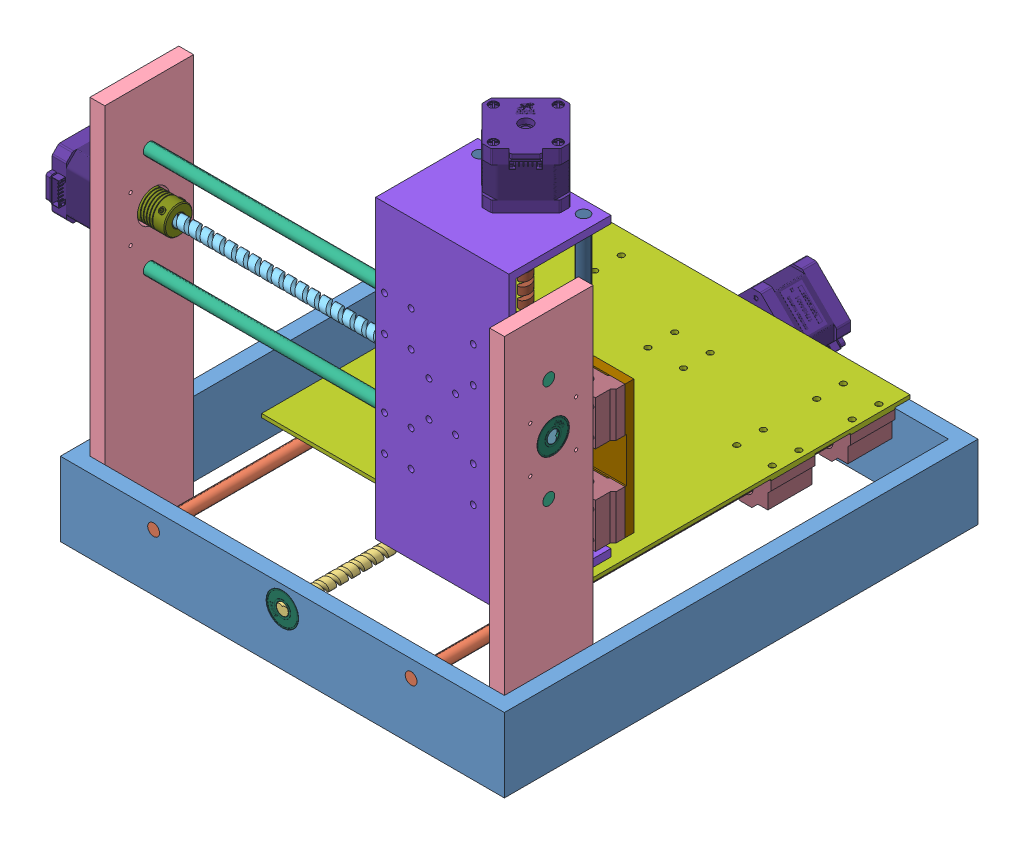
SolidWorks assembly INK Machine 2022, configuration Predeterminado. Lengths in mm.
Overall size (542.6 565 483.23).
40 component instances, 17 part files, 113 mates.
Components (placement in the parent):
- realBASE-1: realBASE [Predeterminado] at (-71.4442 -39.2888 240) size (300 50 320)
- realbarra-1: realbarra [Predeterminado] at (-158.4442 -0.7888 80) x (-0.034704 -0.999398 0) z (0 0 1) size (8 8 320)
- realbarra-2: realbarra [Predeterminado] at (15.5558 -0.7888 80) size (8 8 320)
- realtornillo-1: realtornillo [Predeterminado] at (-71.4442 -3.7888 105) x (-0.003638 0.999993 0) z (0 0 1) size (8.21 8.21 483.23)
- realViga superior-1: realViga superior [Predeterminado] at (68.5558 90.7112 360) x (0 0 1) z (-1 0 0) size (60 260 10)
- realViga superior-2: realViga superior [Predeterminado] at (-201.4442 90.7112 360) x (0 0 1) z (-1 0 0) size (60 260 10)
- realtornillo2-1: realtornillo2 [Predeterminado] at (68.5558 145.7112 357) x (0 0.604417 -0.796668) z (-1 0 0) size (8.21 8.21 482.99)
- realbarra2-1: realbarra2 [Predeterminado] at (68.5558 180.7112 360) x (0 0.764966 -0.644071) z (-1 0 0) size (8 8 280)
- realbarra2-2: realbarra2 [Predeterminado] at (68.5558 110.7112 360) x (0 0.924225 0.381849) z (-1 0 0) size (8 8 280)
- realcama-1: realcama [Predeterminado] at (-71.4442 11.2112 127.5) size (208 3.5 230)
- realCaja superior-5: realCaja superior [Predeterminado] at (13.5558 145.7112 372) x (1 0 0) z (0 0 -1) size (90 200 69)
- realCAMA SUPERIOR-1: realCAMA SUPERIOR [Predeterminado] at (13.5558 104.1528 304.5) x (-1 0 0) z (0 0 -1) size (104 90 6)
- realbarra3-1: realbarra3 [Predeterminado] at (-21.4442 45.7112 316.5) size (8 200 8)
- realbarra3-2: realbarra3 [Predeterminado] at (48.5558 45.7112 316.5) size (8 200 8)
- realtornillo3-1: realtornillo3 [Predeterminado] at (13.5558 222.7112 320.5) x (-0.818193 0 0.574943) z (0 -1 0) size (8.21 8.21 482.52)
- realReklaampastakas 1.step-2: realReklaampastakas 1.step [Predeterminado] at (20.5558 37.5028 293.65) size (20 138.6 10.7)
- realSC8UU.step-1: realSC8UU.step [Predeterminado] at (15.5558 -0.7888 105) size (34 22 30)
- realSC8UU.step-2: realSC8UU.step [Predeterminado] at (-158.4442 -0.7888 105) size (34 22 30)
- realSC8UU.step-3: realSC8UU.step [Predeterminado] at (-158.4442 -0.7888 159) size (34 22 30)
- realSC8UU.step-4: realSC8UU.step [Predeterminado] at (15.5558 -0.7888 159) size (34 22 30)
- realcamisa-1: realcamisa [Predeterminado] at (-71.4442 10.2112 132) x (-1 0 0) z (0 0 1) size (35 28 30)
- realKFL08 - Mancal Flange oval Ø8.stp-1: realKFL08 - Mancal Flange oval Ø8.stp [Predeterminado] at (-71.4442 -3.7888 400.5) x (1 0 0) z (0 1 0) size (22 10.85 22)
- realCHINA_Coupling flexible_D19L25_6,35x8.stp-1: realCHINA_Coupling flexible_D19L25_6,35x8.stp [Predeterminado] at (-71.4442 -3.7888 94.5) x (-0.303541 -0.952818 0) z (-0.952818 0.303541 0) size (19.02 25 19.01)
- realNema 17 Motor a Pasos 17HS4401-1: realNema 17 Motor a Pasos 17HS4401 [Predeterminado] at (-71.4442 -3.7888 42.5) x (0.707107 0.707107 0) z (0 0 1) size (42.2 46.7 62.65)
- realKFL08 - Mancal Flange oval Ø8.stp-2: realKFL08 - Mancal Flange oval Ø8.stp [Predeterminado] at (69.0558 145.7112 357) x (0 -0.381849 0.924225) z (0 -0.924225 -0.381849) size (22 10.85 22)
- realCHINA_Coupling flexible_D19L25_6,35x8.stp-2: realCHINA_Coupling flexible_D19L25_6,35x8.stp [Predeterminado] at (-196.9442 145.7112 357) x (0 -1 0) z (0 0 1) size (19.02 25 19.01)
- realNema 17 Motor a Pasos 17HS4401-2: realNema 17 Motor a Pasos 17HS4401 [Predeterminado] at (-248.9442 145.7112 357) x (0 -1 0) z (1 0 0) size (42.2 46.7 62.65)
- realSC8UU.step-5: realSC8UU.step [Predeterminado] at (-16.4442 110.7112 360) x (0 1 0) z (1 0 0) size (34 22 30)
- realSC8UU.step-6: realSC8UU.step [Predeterminado] at (43.5558 110.7112 360) x (0 1 0) z (1 0 0) size (34 22 30)
- realSC8UU.step-7: realSC8UU.step [Predeterminado] at (43.5558 180.7112 360) x (0 1 0) z (1 0 0) size (34 22 30)
- realSC8UU.step-8: realSC8UU.step [Predeterminado] at (-16.4442 180.7112 360) x (0 1 0) z (1 0 0) size (34 22 30)
- realcamisa-2: realcamisa [Predeterminado] at (13.5558 145.7112 371) x (0 -1 0) z (1 0 0) size (35 28 30)
- realSC8UU.step-9: realSC8UU.step [Predeterminado] at (-21.4442 134.1528 316.5) x (1 0 0) z (0 1 0) size (34 22 30)
- realSC8UU.step-10: realSC8UU.step [Predeterminado] at (-21.4442 74.1528 316.5) x (1 0 0) z (0 1 0) size (34 22 30)
- realSC8UU.step-11: realSC8UU.step [Predeterminado] at (48.5558 134.1528 316.5) x (1 0 0) z (0 1 0) size (34 22 30)
- realSC8UU.step-12: realSC8UU.step [Predeterminado] at (48.5558 74.1528 316.5) x (1 0 0) z (0 1 0) size (34 22 30)
- realKFL08 - Mancal Flange oval Ø8.stp-3: realKFL08 - Mancal Flange oval Ø8.stp [Predeterminado] at (13.5558 45.2112 320.5) size (22 10.85 22)
- realNema 17 Motor a Pasos 17HS4401-3: realNema 17 Motor a Pasos 17HS4401 [Predeterminado] at (13.5558 283.2112 320.5) x (-0.707107 0 0.707107) z (0 -1 0) size (42.2 46.7 62.65)
- realCHINA_Coupling flexible_D19L25_6,35x8.stp-3: realCHINA_Coupling flexible_D19L25_6,35x8.stp [Predeterminado] at (13.5558 231.2112 320.5) x (0.56381 0 0.825904) z (0.825904 0 -0.56381) size (19.02 25 19.01)
- realcamisa-3: realcamisa [Predeterminado] at (13.5558 104.1528 306.5) x (1 0 0) z (0 -1 0) size (35 28 30)
Mates (geometry in assembly coordinates):
- Coincidente1: coincident aligned: plane of BASE-1 through (-221.4442 10.7112 400) normal (0 0 1); plane of tornillo-1 through (-71.4442 -3.7888 400) normal (0 0 1)
- Concéntrica7: concentric aligned: circle of BASE-1; circle of tornillo-1
- Coincidente3: coincident aligned: plane of BASE-1 through (-221.4442 10.7112 400) normal (0 0 1); plane of barra-1 through (-158.4442 -0.7888 400) normal (0 0 1)
- Concéntrica3: concentric aligned: circle of BASE-1; circle of barra-1
- Concéntrica4: concentric aligned: circle of BASE-1; circle of barra-2
- Coincidente6: coincident anti-aligned: plane of BASE-1 through (-211.4442 10.7112 90) normal (1 0 0); plane of Viga superior-2 through (-211.4442 90.7112 360) normal (-1 0 0)
- Coincidente7: coincident anti-aligned: plane of BASE-1 through (-211.4442 10.7112 390) normal (0 0 -1); plane of Viga superior-2 through (-211.4442 220.7112 390) normal (0 0 1)
- Coincidente8: coincident aligned: plane of BASE-1 through (-71.4442 -39.2888 240) normal (0 -1 0); plane of Viga superior-2 through (-211.4442 -39.2888 330) normal (0 -1 0)
- Coincidente9: coincident anti-aligned: plane of BASE-1 through (68.5558 10.7112 90) normal (-1 0 0); plane of Viga superior-1 through (68.5558 90.7112 360) normal (1 0 0)
- Coincidente10: coincident: point of BASE-1; point of Viga superior-1
- Coincidente11: coincident aligned: plane of BASE-1 through (-71.4442 -39.2888 240) normal (0 -1 0); plane of Viga superior-1 through (58.5558 -39.2888 330) normal (0 -1 0)
- Concéntrica11: concentric aligned: circle of Viga superior-1; circle of tornillo2-1
- Concéntrica10: concentric aligned: circle of Viga superior-1; circle of barra2-1
- Concéntrica12: concentric aligned: circle of Viga superior-1; circle of barra2-2
- Paralelo3: parallel anti-aligned: plane of BASE-1 through (-71.4442 -39.2888 240) normal (0 -1 0); plane of cama-1 through (-71.4442 13.7112 127.5) normal (0 1 0)
- Coincidente26: coincident aligned: plane of BASE-1 through (-221.4442 10.7112 400) normal (0 0 1); plane of barra-2 through (15.5558 -0.7888 400) normal (0 0 1)
- Paralelo4: parallel aligned: plane of Viga superior-1 through (68.5558 90.7112 360) normal (1 0 0); plane of barra2-1 through (68.5558 180.7112 360) normal (1 0 0)
- Coincidente29: coincident aligned: plane of Viga superior-1 through (68.5558 90.7112 360) normal (1 0 0); plane of barra2-2 through (68.5558 110.7112 360) normal (1 0 0)
- Coincidente30: coincident aligned: plane of Viga superior-1 through (68.5558 90.7112 360) normal (1 0 0); plane of barra2-1 through (68.5558 180.7112 360) normal (1 0 0)
- Coincidente31: coincident aligned: plane of Viga superior-1 through (68.5558 90.7112 360) normal (1 0 0); plane of tornillo2-1 through (68.5558 145.7112 357) normal (1 0 0)
- Paralelo9: parallel anti-aligned: plane of cama-1 through (-71.4442 13.7112 127.5) normal (0 1 0); plane of Caja superior-5 through (-31.4442 45.7112 377) normal (0 -1 0)
- Concéntrica27: concentric anti-aligned: circle of Caja superior-5; circle of barra3-2
- Coincidente40: coincident aligned: plane of Caja superior-5 through (-31.4442 245.7112 377) normal (0 1 0); plane of barra3-2 through (48.5558 245.7112 316.5) normal (0 1 0)
- Concéntrica28: concentric anti-aligned: circle of Caja superior-5; circle of barra3-1
- Coincidente41: coincident aligned: plane of Caja superior-5 through (-31.4442 245.7112 377) normal (0 1 0); plane of barra3-1 through (-21.4442 245.7112 316.5) normal (0 1 0)
- Coincidente42: coincident aligned: plane of tornillo3-1 through (13.5558 45.7112 320.5) normal (0 -1 0); plane of Caja superior-5 through (-31.4442 45.7112 377) normal (0 -1 0)
- Concéntrica29: concentric aligned: circle of Caja superior-5; circle of tornillo3-1
- Paralelo12: parallel aligned: plane of Viga superior-1 through (68.5558 90.7112 360) normal (1 0 0); plane of CAMA SUPERIOR-1 through (65.5558 59.1528 299.5) normal (1 0 0)
- Coincidente51: coincident anti-aligned: plane of CAMA SUPERIOR-1 through (13.5558 104.1528 299.5) normal (0 0 -1); plane of Reklaampastakas 1.step-2 through (20.5558 37.5028 299.5) normal (0 0 1)
- Coincidente52: coincident aligned: plane of CAMA SUPERIOR-1 through (65.5558 149.1528 299.5) normal (0 1 0); plane of Reklaampastakas 1.step-2 through (30.5558 149.1528 299.5) normal (0 1 0)
- Distancia1: distance = 35 mm aligned: plane of CAMA SUPERIOR-1 through (65.5558 59.1528 299.5) normal (1 0 0); plane of Reklaampastakas 1.step-2 through (30.5558 45.1528 299.5) normal (1 0 0)
- Coincident1: coincident anti-aligned: plane of cama-1 through (-71.4442 10.2112 127.5) normal (0 -1 0); plane of SC8UU.step-1 through (32.5558 10.2112 90) normal (0 1 0)
- Coincident2: coincident aligned: plane of cama-1 through (32.5558 13.7112 310) normal (1 0 0); plane of SC8UU.step-1 through (32.5558 4.2112 90) normal (1 0 0)
- Coincident3: coincident aligned: plane of cama-1 through (32.5558 10.2112 120) normal (0 0 1); plane of SC8UU.step-1 through (15.5558 0.7093 120) normal (0 0 1)
- Coincident4: coincident aligned: plane of cama-1 through (32.5558 13.7112 310) normal (1 0 0); plane of SC8UU.step-4 through (32.5558 4.2112 144) normal (1 0 0)
- Coincident5: coincident anti-aligned: plane of cama-1 through (-71.4442 10.2112 127.5) normal (0 -1 0); plane of SC8UU.step-4 through (32.5558 10.2112 144) normal (0 1 0)
- Coincident6: coincident aligned: plane of cama-1 through (32.5558 10.2112 174) normal (0 0 1); plane of SC8UU.step-4 through (15.5558 0.7093 174) normal (0 0 1)
- Coincident7: coincident aligned: plane of cama-1 through (-175.4442 10.2112 120) normal (0 0 1); plane of SC8UU.step-2 through (-158.4442 0.7093 120) normal (0 0 1)
- Coincident8: coincident aligned: plane of cama-1 through (-141.4442 10.2112 120) normal (1 0 0); plane of SC8UU.step-2 through (-141.4442 4.2112 90) normal (1 0 0)
- Coincident12: coincident aligned: plane of cama-1 through (-175.4442 10.2112 120) normal (0 0 1); plane of SC8UU.step-2 through (-158.4442 0.7093 120) normal (0 0 1)
- Coincident13: coincident anti-aligned: plane of cama-1 through (-71.4442 10.2112 127.5) normal (0 -1 0); plane of SC8UU.step-2 through (-141.4442 10.2112 90) normal (0 1 0)
- Coincident14: coincident aligned: plane of cama-1 through (-175.4442 10.2112 174) normal (0 0 1); plane of SC8UU.step-3 through (-158.4442 0.7093 174) normal (0 0 1)
- Coincident15: coincident aligned: plane of cama-1 through (-175.4442 13.7112 310) normal (-1 0 0); plane of SC8UU.step-3 through (-175.4442 10.2112 144) normal (-1 0 0)
- Coincident17: coincident aligned: plane of cama-1 through (-175.4442 10.2112 174) normal (0 0 1); plane of SC8UU.step-3 through (-158.4442 0.7093 174) normal (0 0 1)
- Coincident18: coincident anti-aligned: plane of cama-1 through (-71.4442 10.2112 127.5) normal (0 -1 0); plane of SC8UU.step-3 through (-165.4442 10.2112 144) normal (0 1 0)
- Concentric1: concentric anti-aligned: cylinder of BASE-1 through (-158.4442 -0.7888 80) axis (0 0 1) radius 4; cylinder of barra-1 through (-158.4442 -0.7888 400) axis (0 0 -1) radius 4
- Concentric2: concentric anti-aligned: cylinder of BASE-1 through (15.5558 -0.7888 80) axis (0 0 1) radius 4; cylinder of barra-2 through (15.5558 -0.7888 400) axis (0 0 -1) radius 4
- Concentric3: concentric aligned: cylinder of barra-2 through (15.5558 -0.7888 400) axis (0 0 -1) radius 4; cylinder of SC8UU.step-4 through (15.5558 -0.7888 144) axis (0 0 -1) radius 5
- Concentric4: concentric aligned: cylinder of barra-1 through (-158.4442 -0.7888 400) axis (0 0 -1) radius 4; cylinder of SC8UU.step-3 through (-158.4442 -0.7888 144) axis (0 0 -1) radius 5
- Concentric5: concentric anti-aligned: cylinder of tornillo-1 through (-71.4442 -3.7888 400) axis (0 0 -1) radius 4; cylinder of camisa-1 through (-71.4442 -3.7888 117) axis (0 0 1) radius 5
- Parallel1: parallel anti-aligned: plane of cama-1 through (-71.4442 11.2112 127.5) normal (0 -1 0); plane of camisa-1 through (-71.4442 10.2112 132) normal (0 1 0)
- Concentric6: concentric anti-aligned: cylinder of BASE-1 through (-71.4442 -3.7888 80) axis (0 0 1) radius 11; cylinder of tornillo-1 through (-71.4442 -3.7888 400) axis (0 0 -1) radius 4
- Width1: width anti-aligned: plane of camisa-1 through (-53.9442 -17.7888 117) normal (0 0 -1); plane of SC8UU.step-2 through (-53.9442 -17.7888 147) normal (0 0 1); plane of camisa-1 through (-158.4442 0.7093 120) normal (0 0 1); plane of SC8UU.step-3 through (-158.4442 0.7093 144) normal (0 0 -1)
- Coincident19: coincident anti-aligned: plane of BASE-1 through (-211.4442 10.7112 390) normal (0 0 -1); plane of SC8UU.step-3 through (-158.4442 0.7093 174) normal (0 0 1)
- Coincident20: coincident anti-aligned: plane of BASE-1 through (-211.4442 10.7112 90) normal (0 0 1); plane of SC8UU.step-2 through (-158.4442 0.7093 90) normal (0 0 -1)
- Concentric7: concentric anti-aligned: cylinder of tornillo-1 through (-71.4442 -3.7888 400) axis (0 0 -1) radius 4; cylinder of KFL08 - Mancal Flange oval Ø8.stp-1 through (-71.4442 -3.7888 394.575) axis (0 0 1) radius 4
- Coincident21: coincident aligned: plane of BASE-1 through (-221.4442 10.7112 400) normal (0 0 1); plane of KFL08 - Mancal Flange oval Ø8.stp-1 through (-70.7711 1.6853 400) normal (0 0 1)
- Concentric8: concentric aligned: cylinder of tornillo-1 through (-71.4442 -3.7888 400) axis (0 0 -1) radius 4; cylinder of CHINA_Coupling flexible_D19L25_6,35x8.stp-1 through (-71.4442 -3.7888 106.9) axis (0 0 -1) radius 4
- Concentric9: concentric aligned: cylinder of CHINA_Coupling flexible_D19L25_6,35x8.stp-1 through (-71.4442 -3.7888 94.5) axis (0 0 1) radius 3.175; cylinder of Nema 17 Motor a Pasos 17HS4401-1 through (-71.4442 -3.7888 80) axis (0 0 1) radius 2.5
- Coincident24: coincident anti-aligned: plane of CHINA_Coupling flexible_D19L25_6,35x8.stp-1 through (-79.9243 -1.0873 82) normal (0 0 -1); plane of Nema 17 Motor a Pasos 17HS4401-1 through (-71.4442 -3.7888 82) normal (0 0 1)
- Coincident25: coincident anti-aligned: plane of BASE-1 through (-221.4442 10.7112 80) normal (0 0 -1); plane of Nema 17 Motor a Pasos 17HS4401-1 through (-71.4442 -3.7888 80) normal (0 0 1)
- Parallel3: parallel aligned: plane of cama-1 through (-71.4442 13.7112 127.5) normal (0 1 0); plane of Nema 17 Motor a Pasos 17HS4401-1 through (-68.2622 22.7277 42.5) normal (0 1 0)
- Concentric10: concentric aligned: cylinder of Viga superior-1 through (58.5558 145.7112 357) axis (1 0 0) radius 11; cylinder of KFL08 - Mancal Flange oval Ø8.stp-2 through (65.0558 145.7112 357) axis (1 0 0) radius 11
- Coincident27: coincident aligned: plane of Viga superior-1 through (68.5558 90.7112 360) normal (1 0 0); plane of KFL08 - Mancal Flange oval Ø8.stp-2 through (68.5558 140.3948 355.5318) normal (1 0 0)
- Coincident28: coincident anti-aligned: plane of CHINA_Coupling flexible_D19L25_6,35x8.stp-2 through (-209.4442 145.7112 365.9) normal (-1 0 0); plane of Nema 17 Motor a Pasos 17HS4401-2 through (-209.4442 145.7112 357) normal (1 0 0)
- Concentric11: concentric aligned: cylinder of CHINA_Coupling flexible_D19L25_6,35x8.stp-2 through (-196.9442 145.7112 357) axis (1 0 0) radius 3.175; cylinder of Nema 17 Motor a Pasos 17HS4401-2 through (-211.4442 145.7112 357) axis (1 0 0) radius 2.5
- Coincident29: coincident anti-aligned: plane of Viga superior-2 through (-211.4442 90.7112 360) normal (-1 0 0); plane of Nema 17 Motor a Pasos 17HS4401-2 through (-211.4442 145.7112 357) normal (1 0 0)
- Concentric12: concentric anti-aligned: cylinder of tornillo2-1 through (-186.4442 145.7112 357) axis (1 0 0) radius 4; cylinder of CHINA_Coupling flexible_D19L25_6,35x8.stp-2 through (-184.5442 145.7112 357) axis (-1 0 0) radius 4
- Parallel4: parallel aligned: plane of Viga superior-2 through (-211.4442 220.7112 330) normal (0 1 0); plane of Nema 17 Motor a Pasos 17HS4401-2 through (-218.9442 166.7112 340.5) normal (0 1 0)
- Coincident31: coincident anti-aligned: plane of Caja superior-5 through (13.5558 145.7112 371) normal (0 0 -1); plane of SC8UU.step-5 through (-31.4442 127.7112 371) normal (0 0 1)
- Coincident32: coincident aligned: plane of Caja superior-5 through (-31.4442 45.7112 377) normal (-1 0 0); plane of SC8UU.step-5 through (-31.4442 110.7112 361.4981) normal (-1 0 0)
- Coincident33: coincident aligned: plane of Caja superior-5 through (-1.4442 127.7112 371) normal (0 1 0); plane of SC8UU.step-5 through (-31.4442 127.7112 365) normal (0 1 0)
- Coincident34: coincident aligned: plane of Caja superior-5 through (28.5558 127.7112 371) normal (0 1 0); plane of SC8UU.step-6 through (28.5558 127.7112 365) normal (0 1 0)
- Coincident35: coincident aligned: plane of Caja superior-5 through (28.5558 127.7112 371) normal (-1 0 0); plane of SC8UU.step-6 through (28.5558 110.7112 361.4981) normal (-1 0 0)
- Coincident36: coincident anti-aligned: plane of Caja superior-5 through (13.5558 145.7112 371) normal (0 0 -1); plane of SC8UU.step-6 through (28.5558 127.7112 371) normal (0 0 1)
- Coincident37: coincident aligned: plane of Caja superior-5 through (58.5558 197.7112 371) normal (0 1 0); plane of SC8UU.step-7 through (28.5558 197.7112 365) normal (0 1 0)
- Coincident38: coincident aligned: plane of Caja superior-5 through (28.5558 163.7112 371) normal (-1 0 0); plane of SC8UU.step-7 through (28.5558 180.7112 361.4981) normal (-1 0 0)
- Coincident39: coincident anti-aligned: plane of Caja superior-5 through (13.5558 145.7112 371) normal (0 0 -1); plane of SC8UU.step-7 through (28.5558 197.7112 371) normal (0 0 1)
- Coincident40: coincident anti-aligned: plane of Caja superior-5 through (13.5558 145.7112 371) normal (0 0 -1); plane of SC8UU.step-8 through (-31.4442 197.7112 371) normal (0 0 1)
- Coincident41: coincident aligned: plane of Caja superior-5 through (-31.4442 45.7112 377) normal (-1 0 0); plane of SC8UU.step-8 through (-31.4442 180.7112 361.4981) normal (-1 0 0)
- Coincident42: coincident aligned: plane of Caja superior-5 through (-31.4442 197.7112 371) normal (0 1 0); plane of SC8UU.step-8 through (-31.4442 197.7112 365) normal (0 1 0)
- Concentric14: concentric anti-aligned: cylinder of barra2-1 through (-211.4442 180.7112 360) axis (1 0 0) radius 4; cylinder of SC8UU.step-8 through (-31.4442 180.7112 360) axis (-1 0 0) radius 5
- Coincident43: coincident anti-aligned: plane of Viga superior-1 through (58.5558 90.7112 360) normal (-1 0 0); plane of SC8UU.step-7 through (58.5558 180.7112 361.4981) normal (1 0 0)
- Coincident44: coincident anti-aligned: plane of Viga superior-2 through (-201.4442 90.7112 360) normal (1 0 0); plane of SC8UU.step-5 through (-143.5585 110.7112 361.4981) normal (-1 0 0)
- Concentric17: concentric aligned: cylinder of tornillo2-1 through (-186.4442 145.7112 357) axis (1 0 0) radius 4; cylinder of camisa-2 through (-1.4442 145.7112 357) axis (1 0 0) radius 5
- Parallel6: parallel aligned: plane of Caja superior-5 through (-31.4442 245.7112 377) normal (0 1 0); plane of camisa-2 through (28.5558 163.2112 343) normal (0 1 0)
- Width2: width anti-aligned: plane of SC8UU.step-7 through (28.5558 180.7112 361.4981) normal (-1 0 0); plane of camisa-2 through (-1.4442 180.7112 361.4981) normal (1 0 0); plane of SC8UU.step-8 through (28.5558 163.2112 343) normal (1 0 0); plane of camisa-2 through (-1.4442 163.2112 343) normal (-1 0 0)
- Coincident46: coincident anti-aligned: plane of CAMA SUPERIOR-1 through (13.5558 104.1528 305.5) normal (0 0 1); plane of SC8UU.step-9 through (-28.4442 119.1528 305.5) normal (0 0 -1)
- Coincident47: coincident aligned: plane of CAMA SUPERIOR-1 through (65.5558 149.1528 299.5) normal (0 1 0); plane of SC8UU.step-9 through (-21.4442 149.1528 315.0019) normal (0 1 0)
- Coincident48: coincident aligned: plane of CAMA SUPERIOR-1 through (-4.4442 149.1528 305.5) normal (1 0 0); plane of SC8UU.step-9 through (-4.4442 119.1528 311.5) normal (1 0 0)
- Coincident49: coincident anti-aligned: plane of CAMA SUPERIOR-1 through (13.5558 104.1528 305.5) normal (0 0 1); plane of SC8UU.step-10 through (-4.4442 59.1528 305.5) normal (0 0 -1)
- Coincident50: coincident aligned: plane of CAMA SUPERIOR-1 through (-38.4442 89.1528 305.5) normal (0 1 0); plane of SC8UU.step-10 through (-21.4442 89.1528 315.0019) normal (0 1 0)
- Coincident51: coincident aligned: plane of CAMA SUPERIOR-1 through (-4.4442 59.1528 305.5) normal (1 0 0); plane of SC8UU.step-10 through (-4.4442 59.1528 311.5) normal (1 0 0)
- Coincident52: coincident anti-aligned: plane of CAMA SUPERIOR-1 through (13.5558 104.1528 305.5) normal (0 0 1); plane of SC8UU.step-11 through (41.5558 119.1528 305.5) normal (0 0 -1)
- Coincident53: coincident aligned: plane of CAMA SUPERIOR-1 through (65.5558 59.1528 299.5) normal (1 0 0); plane of SC8UU.step-11 through (65.5558 119.1528 311.5) normal (1 0 0)
- Coincident54: coincident aligned: plane of CAMA SUPERIOR-1 through (65.5558 149.1528 299.5) normal (0 1 0); plane of SC8UU.step-11 through (48.5558 149.1528 315.0019) normal (0 1 0)
- Coincident55: coincident anti-aligned: plane of CAMA SUPERIOR-1 through (13.5558 104.1528 305.5) normal (0 0 1); plane of SC8UU.step-12 through (65.5558 59.1528 305.5) normal (0 0 -1)
- Coincident56: coincident aligned: plane of CAMA SUPERIOR-1 through (65.5558 89.1528 305.5) normal (0 1 0); plane of SC8UU.step-12 through (48.5558 89.1528 315.0019) normal (0 1 0)
- Coincident57: coincident aligned: plane of CAMA SUPERIOR-1 through (65.5558 59.1528 299.5) normal (1 0 0); plane of SC8UU.step-12 through (65.5558 59.1528 311.5) normal (1 0 0)
- Concentric18: concentric aligned: cylinder of barra3-2 through (48.5558 245.7112 316.5) axis (0 -1 0) radius 4; cylinder of SC8UU.step-11 through (48.5558 119.1528 316.5) axis (0 -1 0) radius 5
- Concentric19: concentric aligned: cylinder of Caja superior-5 through (13.5558 245.7112 320.5) axis (0 -1 0) radius 11; cylinder of KFL08 - Mancal Flange oval Ø8.stp-3 through (13.5558 49.2112 320.5) axis (0 -1 0) radius 11
- Coincident59: coincident aligned: plane of Caja superior-5 through (-31.4442 45.7112 377) normal (0 -1 0); plane of KFL08 - Mancal Flange oval Ø8.stp-3 through (14.8897 45.7112 331.3479) normal (0 -1 0)
- Concentric20: concentric aligned: cylinder of Nema 17 Motor a Pasos 17HS4401-3 through (13.5558 245.7112 320.5) axis (0 -1 0) radius 2.5; cylinder of CHINA_Coupling flexible_D19L25_6,35x8.stp-3 through (13.5558 231.2112 320.5) axis (0 -1 0) radius 3.175
- Coincident60: coincident anti-aligned: plane of Nema 17 Motor a Pasos 17HS4401-3 through (13.5558 243.7112 320.5) normal (0 -1 0); plane of CHINA_Coupling flexible_D19L25_6,35x8.stp-3 through (20.9064 243.7112 315.4821) normal (0 1 0)
- Concentric21: concentric aligned: cylinder of tornillo3-1 through (13.5558 45.7112 320.5) axis (0 1 0) radius 4; cylinder of CHINA_Coupling flexible_D19L25_6,35x8.stp-3 through (13.5558 218.8112 320.5) axis (0 1 0) radius 4
- Coincident61: coincident anti-aligned: plane of Caja superior-5 through (-31.4442 245.7112 377) normal (0 1 0); plane of Nema 17 Motor a Pasos 17HS4401-3 through (13.5558 245.7112 320.5) normal (0 -1 0)
- Parallel8: parallel aligned: plane of Caja superior-5 through (13.5558 145.7112 377) normal (0 0 1); plane of Nema 17 Motor a Pasos 17HS4401-3 through (16.7378 253.2112 347.0165) normal (0 0 1)
- Coincident62: coincident anti-aligned: plane of Caja superior-5 through (-31.4442 50.7112 308) normal (0 1 0); plane of SC8UU.step-12 through (48.5558 50.7112 315.0019) normal (0 -1 0)
- Concentric22: concentric anti-aligned: cylinder of tornillo3-1 through (13.5558 45.7112 320.5) axis (0 1 0) radius 4; cylinder of camisa-3 through (13.5558 119.1528 320.5) axis (0 -1 0) radius 5
- Parallel9: parallel aligned: plane of CAMA SUPERIOR-1 through (13.5558 104.1528 304.5) normal (0 0 1); plane of camisa-3 through (13.5558 104.1528 334.5) normal (0 0 1)
- Width3: width anti-aligned: plane of SC8UU.step-10 through (-6.4442 59.1528 323.5) normal (1 0 0); plane of camisa-3 through (33.5558 59.1528 313.5) normal (-1 0 0); plane of SC8UU.step-12 through (-3.9442 89.1528 334.5) normal (-1 0 0); plane of camisa-3 through (31.0558 89.1528 334.5) normal (1 0 0)
- Coincident63: coincident anti-aligned: plane of SC8UU.step-10 through (-21.4442 89.1528 315.0019) normal (0 1 0); plane of camisa-3 through (-3.9442 89.1528 334.5) normal (0 -1 0)
- Coincident64: coincident anti-aligned: plane of realViga superior-1 through (58.5558 90.7112 360) normal (-1 0 0); plane of realSC8UU.step-7 through (58.5558 180.7112 361.4981) normal (1 0 0)
